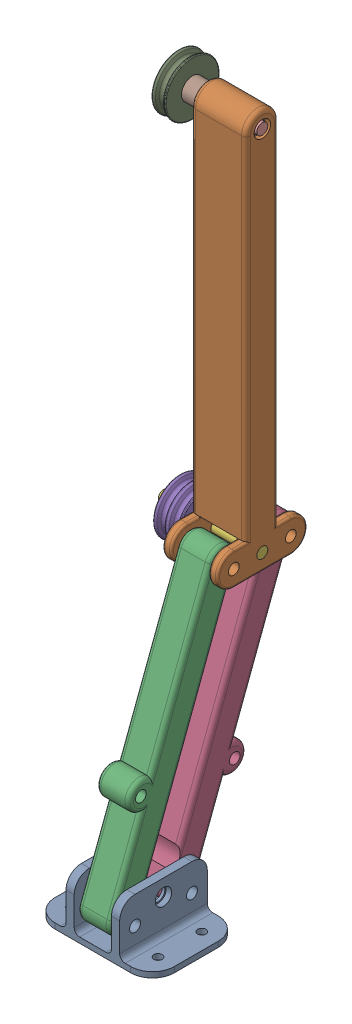
SolidWorks assembly Arm Assem, configuration Default. Lengths in mm.
Overall size (77.47 397.22 129.71).
10 component instances, 8 part files, 20 mates.
Components (placement in the parent):
- Mounting Bracket-1: Mounting Bracket [Default] at origin size (69.22 31.75 50.8)
- Contact Arm-1: Contact Arm [Default] at (-15.875 166.7605 -48.1016) x (0 1 0) z (1 0 0) size (231.78 52.07 31.75)
- Parallel Arm-2: Parallel Arm [Default] at (9.525 91.3177 13.4142) x (0 0.935492 -0.353348) z (0 0.353348 0.935492) size (177.8 19.05 26.35)
- Parallel Arm-5: Parallel Arm [Default] at (-9.525 91.3177 -19.6058) x (0 0.935492 -0.353348) z (0 -0.353348 -0.935492) size (177.8 19.05 26.35)
- Elbow Pulley-1: Elbow Pulley [Default] at (-20.6687 166.7605 -31.5916) x (0 -0.025414 -0.999677) z (1 0 0) size (31.4 31.4 15.05)
- Elbow Pulley Shaft-1: Elbow Pulley Shaft [Default] at (15.875 166.7605 -31.5916) x (0 0 1) z (-1 0 0) size (6.35 6.35 57.15)
- Elbow Pulley Washer-1: Elbow Pulley Washer [Default] at (-16.6687 166.7605 -31.5916) x (0 -0.99991 0.013398) z (0 0.013398 0.99991) size (12.7 0.79 12.7)
- End Pulley Spacer-1: End Pulley Spacer [Default] at (-24.6687 379.4855 -31.5916) x (0 0 -1) z (1 0 0) size (12.7 12.7 8.79)
- Base Pulley-1: Base Pulley [Default] at (-28.6687 379.4855 -31.5916) x (0 0.139265 0.990255) z (-1 0 0) size (31.4 31.4 8)
- Elbow Pulley Shaft-2: Elbow Pulley Shaft [Default] at (15.875 379.4855 -31.5916) x (0 0 1) z (-1 0 0) size (6.35 6.35 57.15)
Mates (geometry in assembly coordinates):
- Concentric2: concentric: cylinder of Mounting Bracket-1 through (36.195 15.875 41.91) axis (-1 0 0) radius 3.175; cylinder of Parallel Arm-2 through (-9.525 15.875 41.91) axis (1 0 0) radius 3.1115
- Concentric5: concentric: cylinder of Contact Arm-1 through (15.875 166.7605 -15.0816) axis (-1 0 0) radius 3.1115; cylinder of Parallel Arm-2 through (-9.525 166.7605 -15.0816) axis (1 0 0) radius 3.1115
- Parallel1: parallel: plane of Parallel Arm-2 through (-9.525 12.9581 34.1875) normal (0 -0.353348 -0.935492); plane of Parallel Arm-5 through (9.525 18.7919 16.6125) normal (0 0.353348 0.935492)
- Concentric8: concentric: cylinder of Mounting Bracket-1 through (36.195 15.875 8.89) axis (-1 0 0) radius 3.175; cylinder of Parallel Arm-5 through (9.525 15.875 8.89) axis (-1 0 0) radius 3.1115
- Width2: width: plane of Contact Arm-1 through (10.795 176.2855 -48.1016) normal (-1 0 0); plane of Contact Arm-1 through (-10.795 176.2855 -48.1016) normal (1 0 0); plane of Parallel Arm-5 through (-9.525 15.875 8.89) normal (-1 0 0); plane of Parallel Arm-5 through (9.525 15.875 8.89) normal (1 0 0)
- Concentric9: concentric: cylinder of Contact Arm-1 through (15.875 166.7605 -48.1016) axis (-1 0 0) radius 3.1115; cylinder of Parallel Arm-5 through (9.525 166.7605 -48.1016) axis (-1 0 0) radius 3.1115
- Concentric10: concentric: cylinder of Contact Arm-1 through (15.875 166.7605 -31.5916) axis (-1 0 0) radius 3.1115; cylinder of Elbow Pulley Shaft-1 through (-41.275 166.7605 -31.5916) axis (1 0 0) radius 3.175
- Coincident8: coincident: plane of Contact Arm-1 through (15.875 166.7605 -48.1016) normal (1 0 0); plane of Elbow Pulley Shaft-1 through (15.875 166.7605 -31.5916) normal (1 0 0)
- Concentric11: concentric: cylinder of Elbow Pulley Shaft-1 through (-41.275 166.7605 -31.5916) axis (1 0 0) radius 3.175; cylinder of Elbow Pulley-1 through (-24.1938 166.7605 -31.5916) axis (-1 0 0) radius 6.35
- Concentric12: concentric: cylinder of Elbow Pulley Shaft-1 through (-41.275 166.7605 -31.5916) axis (1 0 0) radius 3.175; cylinder of Elbow Pulley Washer-1 through (-15.875 166.7605 -31.5916) axis (-1 0 0) radius 3.175
- Coincident9: coincident: plane of Contact Arm-1 through (-15.875 166.7605 -48.1016) normal (-1 0 0); plane of Elbow Pulley Washer-1 through (-15.875 166.7605 -31.5916) normal (1 0 0)
- Coincident10: coincident: plane of Elbow Pulley-1 through (-16.6687 166.7605 -31.5916) normal (1 0 0); plane of Elbow Pulley Washer-1 through (-16.6687 166.7605 -31.5916) normal (-1 0 0)
- Coincident16: coincident: plane of Contact Arm-1 through (-15.875 166.7605 -48.1016) normal (-1 0 0); plane of End Pulley Spacer-1 through (-15.875 379.4855 -31.5916) normal (1 0 0)
- Coincident17: coincident: plane of End Pulley Spacer-1 through (-24.6687 379.4855 -31.5916) normal (-1 0 0); plane of Base Pulley-1 through (-24.6687 379.4855 -31.5916) normal (1 0 0)
- Concentric20: concentric: cylinder of Contact Arm-1 through (15.875 381.073 -31.5916) axis (-1 0 0) radius 3.1115; cylinder of Elbow Pulley Shaft-2 through (-41.275 381.073 -31.5916) axis (1 0 0) radius 3.175
- Coincident18: coincident: plane of Contact Arm-1 through (15.875 166.7605 -48.1016) normal (1 0 0); plane of Elbow Pulley Shaft-2 through (15.875 379.4855 -31.5916) normal (1 0 0)
- Concentric22: concentric: cylinder of End Pulley Spacer-1 through (-15.875 379.4855 -31.5916) axis (-1 0 0) radius 3.175; cylinder of Elbow Pulley Shaft-2 through (-41.275 379.4855 -31.5916) axis (1 0 0) radius 3.175
- Concentric23: concentric: cylinder of Base Pulley-1 through (-24.6687 379.4855 -31.5916) axis (-1 0 0) radius 4.7625; cylinder of Elbow Pulley Shaft-2 through (-41.275 379.4855 -31.5916) axis (1 0 0) radius 3.175
- Coincident19: coincident: plane of Parallel Arm-2 through (-9.525 15.875 41.91) normal (-1 0 0); plane of Parallel Arm-5 through (-9.525 15.875 8.89) normal (-1 0 0)
- Width1: width: plane of Parallel Arm-2 through (-9.525 15.875 41.91) normal (-1 0 0); plane of Parallel Arm-2 through (9.525 15.875 41.91) normal (1 0 0); plane of Mounting Bracket-1 through (-10.795 6.35 50.8) normal (1 0 0); plane of Mounting Bracket-1 through (10.795 34.925 50.8) normal (-1 0 0)
